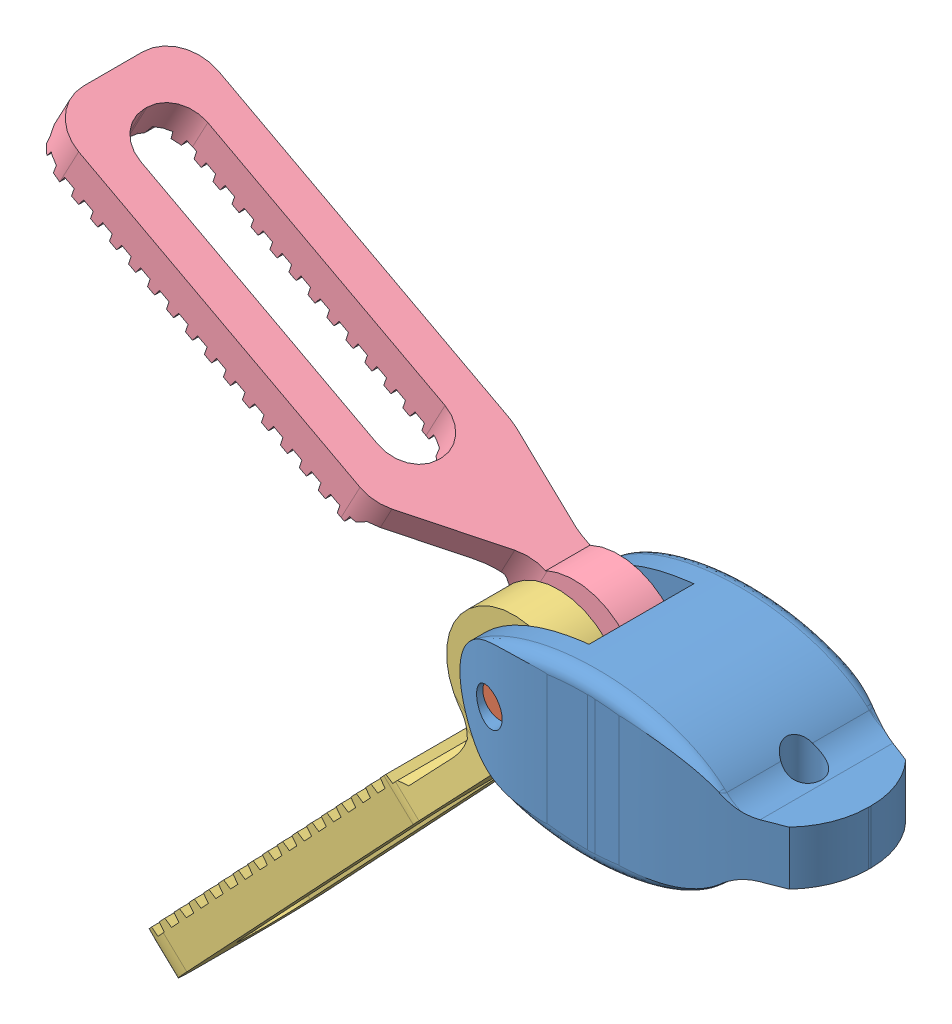
SolidWorks assembly Tool_Wrists_Cadiere_Forceps, configuration 默认. Lengths in mm.
Overall size (30.04 27.77 6.88).
4 component instances, 4 part files, 6 mates.
Components (placement in the parent):
- Tool_Wristis_Caudier_Forceps_Link_2-1: Tool_Wristis_Caudier_Forceps_Link_2 [Default] at (-1.612 0.3435 10.0669) size (13.22 7.35 6.88)
- Tool_Wristis_Caudiere_Forceps_shaft_Link_2_3-1: Tool_Wristis_Caudiere_Forceps_shaft_Link_2_3 [Default] at (-5.412 0.3435 10.6669) size (1.3 1.3 5)
- Tool_Wristis_Caudiere_forceps_Link_3_Left-1: Tool_Wristis_Caudiere_forceps_Link_3_Left [Default] at (-5.412 0.3435 13.5169) x (-0.728573 0.684968 0) z (0 0 1) size (5 22.4 5.2)
- Tool_Wristis_Caudiere_forceps_Link_3_Right-1: Tool_Wristis_Caudiere_forceps_Link_3_Right [Default] at (-5.412 0.3435 12.9169) x (-0.470208 -0.882556 0) z (0 0 -1) size (5 22.4 5.2)
Mates (geometry in assembly coordinates):
- Concentric1: concentric aligned: cylinder of Tool_Wristis_Caudier_Forceps_Link_2-1 through (-5.412 0.3435 16.6581) axis (0 0 -1) radius 0.65; cylinder of Tool_Wristis_Caudiere_Forceps_shaft_Link_2_3-1 through (-5.412 0.3435 15.6669) axis (0 0 -1) radius 0.65
- Distance1: distance = 4.5 mm aligned: plane of Tool_Wristis_Caudier_Forceps_Link_2-1 through (-7.612 -3.3319 15.1669) normal (0 0 -1); plane of Tool_Wristis_Caudiere_Forceps_shaft_Link_2_3-1 through (-5.412 0.3435 10.6669) normal (0 0 -1)
- Concentric2: concentric anti-aligned: cylinder of Tool_Wristis_Caudiere_Forceps_shaft_Link_2_3-1 through (-5.412 0.3435 15.6669) axis (0 0 -1) radius 0.65; cylinder of Tool_Wristis_Caudiere_forceps_Link_3_Left-1 through (-5.412 0.3435 13.5169) axis (0 0 1) radius 0.65
- Coincident2: coincident anti-aligned: plane of Tool_Wristis_Caudier_Forceps_Link_2-1 through (-7.612 -3.3319 15.1669) normal (0 0 -1); plane of Tool_Wristis_Caudiere_forceps_Link_3_Left-1 through (-5.412 0.3435 15.1669) normal (0 0 1)
- Concentric3: concentric aligned: cylinder of Tool_Wristis_Caudiere_Forceps_shaft_Link_2_3-1 through (-5.412 0.3435 15.6669) axis (0 0 -1) radius 0.65; cylinder of Tool_Wristis_Caudiere_forceps_Link_3_Right-1 through (-5.412 0.3435 12.9169) axis (0 0 -1) radius 0.65
- Coincident3: coincident anti-aligned: plane of Tool_Wristis_Caudier_Forceps_Link_2-1 through (-7.612 -3.3319 11.2669) normal (0 0 1); plane of Tool_Wristis_Caudiere_forceps_Link_3_Right-1 through (-5.412 0.3435 11.2669) normal (0 0 -1)
